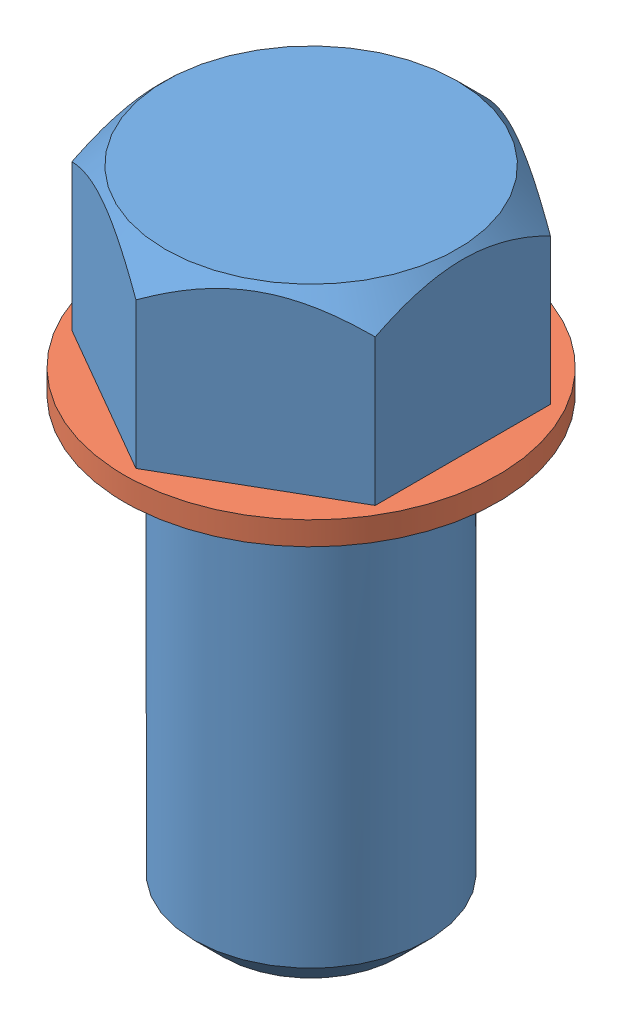
SolidWorks assembly Bolt_Assembly, configuration 0.5 in HRD. Lengths in mm.
Overall size (20.32 34.92 20.32).
2 component instances, 2 part files, 1 mates.
Components (placement in the parent):
- Bolt-1: Bolt [.5 bolt] at origin size (16.5 34.92 19.05)
- Washer-1: Washer [.5 washer] at (0 24.13 0) size (20.32 1.27 20.32)
Mates (geometry in assembly coordinates):
- ProfileCenter1: profile center anti-aligned: circle of Washer-1; circle of Bolt-1
